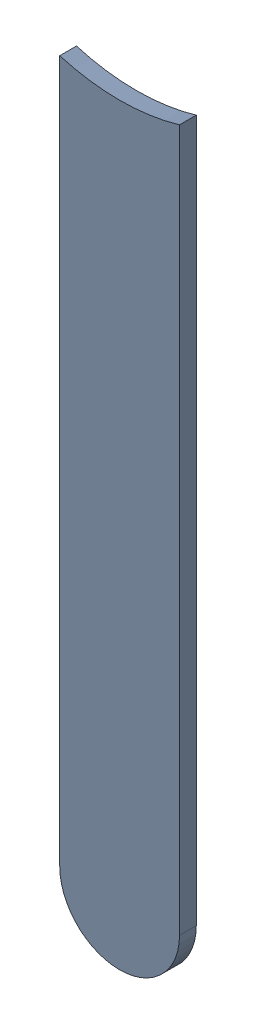
SolidWorks assembly Track (18.08mm,41.48mm)(18.08mm,43.4mm) on Bottom Layer, configuration Predeterminado. Lengths in mm.
Overall size (0.25 1.62 0.04).
2 component instances, 1 part files, 0 mates.
Components (placement in the parent):
- Track (18.08mm,41.48mm)(18.08mm,43.4mm) on Bottom Layer-1-1: Track (18.08mm,41.48mm)(18.08mm,43.4mm) on Bottom Layer-1 [Predeterminado] at (-68.317 -44.187 -0.4013) size (0.25 1.62 0.04)
  - Track (18.08mm,41.48mm)(18.08mm,43.4mm) on Bottom Layer-Part-1-1: Track (18.08mm,41.48mm)(18.08mm,43.4mm) on Bottom Layer-Part-1 [Predeterminado] at origin size (0.25 1.62 0.04)
